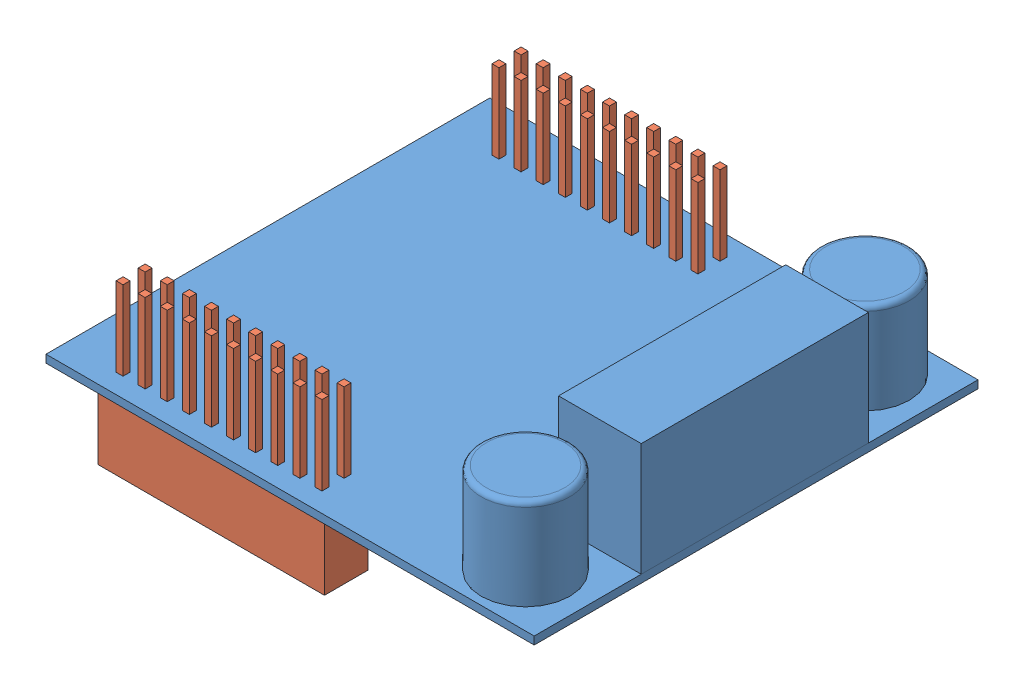
SolidWorks assembly boosterpack, configuration Standard. Lengths in mm.
Overall size (56.1 22.4 51).
3 component instances, 2 part files, 6 mates.
Components (placement in the parent):
- boosterpack-1: boosterpack [Standard] at origin size (56.1 13.9 51)
- pin_header-1: pin_header [Standard] at (-10.45 0 -21.6) x (-1 0 0) z (0 0 1) size (26 18.5 5)
- pin_header-2: pin_header [Standard] at (-10.45 0 21.6) x (-1 0 0) z (0 0 1) size (26 18.5 5)
Mates (geometry in assembly coordinates):
- Deckungsgleich1: coincident anti-aligned: plane of boosterpack-1 through (0 0 0) normal (0 -1 0); plane of pin_header-1 through (-10.45 0 -21.6) normal (0 1 0)
- Deckungsgleich2: coincident anti-aligned: plane of boosterpack-1 through (0 0 0) normal (0 -1 0); plane of pin_header-2 through (-10.45 0 21.6) normal (0 1 0)
- Abstand1: distance = 4.6 mm aligned: plane of boosterpack-1 through (-28.05 0.9 25.5) normal (-1 0 0); plane of pin_header-2 through (-23.45 -8.5 24.1) normal (-1 0 0)
- Deckungsgleich4: coincident aligned: plane of pin_header-1 through (-23.45 -8.5 -19.1) normal (-1 0 0); plane of pin_header-2 through (-23.45 -8.5 24.1) normal (-1 0 0)
- Abstand3: distance = 24.1 mm: plane of assembly through (0 0 0) normal (0 0 1); plane of assembly; plane of pin_header-2 through (2.55 -8.5 24.1) normal (0 0 1)
- Abstand4: distance = 24.1 mm anti-aligned: plane of pin_header-1 through (2.55 -8.5 -24.1) normal (0 0 -1); plane of assembly through (0 0 0) normal (0 0 1)
